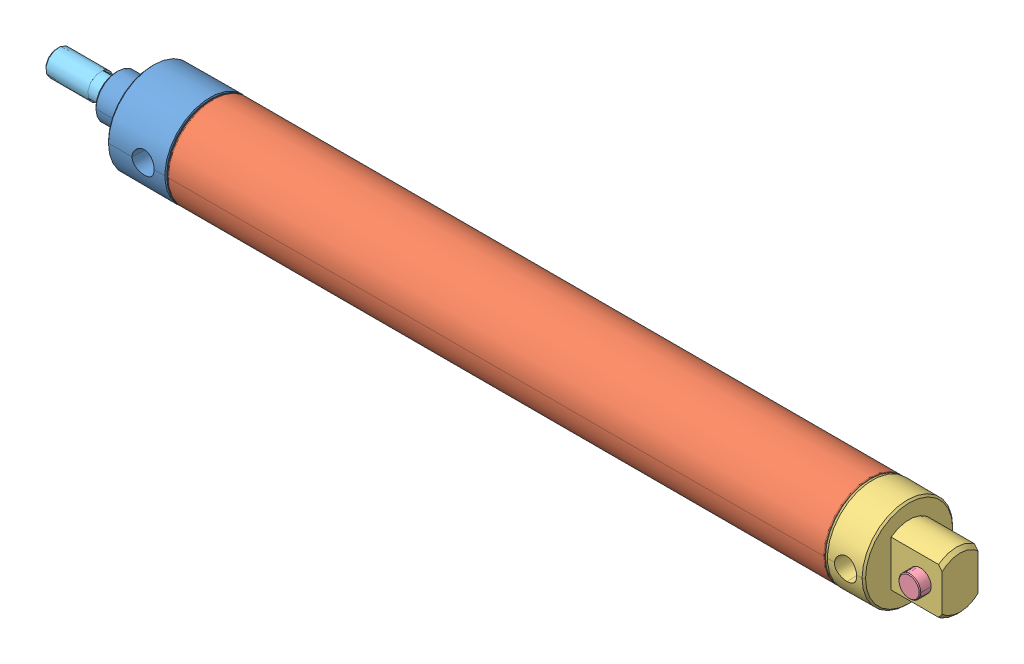
SolidWorks assembly 1710_DP, configuration Default. Lengths in mm.
Overall size (394.08 53.92 53.92).
5 component instances, 5 part files, 2 mates.
Components (placement in the parent):
- _17R000_0_rod_guide_4-1: _17R000_0_rod_guide_4 [Default] at origin size (47.63 39.54 39.54)
- _17R_11_30250C_6-1: _17R_11_30250C_6 [Default] at (42.2275 0 0) size (288.92 39.54 39.54)
- _17P0000_rear_head_8-1: _17P0000_rear_head_8 [Default] at (323.977 0 0) size (44.45 39.54 39.61)
- _D_358_10-1: _D_358_10 [Default] at (358.902 0 0) x (1 0 0) z (0 0 -1) size (9.53 9.53 25.4)
- _C_1710_DP0000_rod_12-1: _C_1710_DP0000_rod_12 [Default] at (-0.254 0 0) x (1 0 0) z (0 -0.769373 0.6388) size (349.38 38.29 38.29)
Mates (geometry in assembly coordinates):
- Concentric1: concentric: cylinder of _17R000_0_rod_guide_4-1 through (15.875 0 0) axis (-1 0 0) radius 9.525; cylinder of _C_1710_DP0000_rod_12-1 through (-6.604 0 0) axis (-1 0 0) radius 5.5563
- LimitDistance2: limit distance = 25.654 mm: plane of _17R000_0_rod_guide_4-1 through (0 0 0) normal (-1 0 0); plane of _C_1710_DP0000_rod_12-1 through (-25.654 0 0) normal (-1 0 0)
